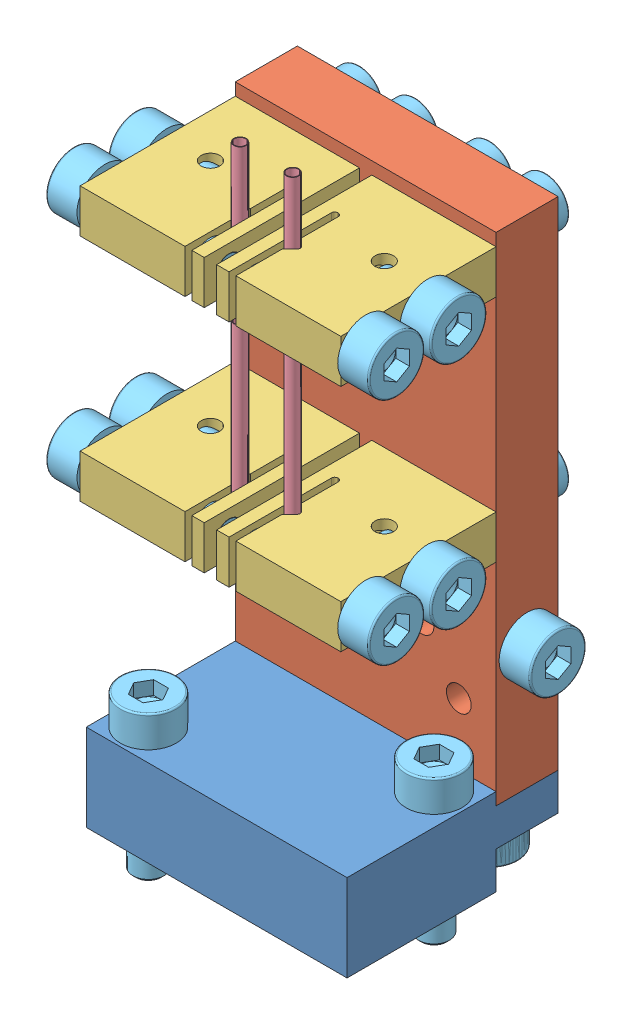
SolidWorks assembly OvenAssembly_r3, configuration Default. Lengths in mm.
Overall size (26 53 19.75).
32 component instances, 5 part files, 47 mates.
Components (placement in the parent):
- OvenBase_r3-1: OvenBase_r3 [Default] at (5.2062 4.9823 14.2147) size (21 7 17)
- OvenBack_r3-1: OvenBack_r3 [Default] at (5.2062 10.9823 8.2147) size (21 40 5)
- OvenSide_r3-1: OvenSide_r3 [Default] at (10.7062 46.4823 16.9647) x (0 0 1) z (-1 0 0) size (12.5 3.5 10)
- OvenSide_r3-2: OvenSide_r3 [Default] at (10.7062 27.9823 16.9647) x (0 0 1) z (-1 0 0) size (12.5 3.5 10)
- OvenTube-1: OvenTube [Default] at (7.3269 27.9823 18.7147) size (1 27 1)
- socket head cap screw_iso-10: socket head cap screw_iso [ISO 4762 M2.5 x 10 - 10N] at (18.2062 29.7323 21.2147) x (-1 0 0) z (0 0 -1) size (12.5 4.5 4.5)
- socket head cap screw_iso-12: socket head cap screw_iso [ISO 4762 M2.5 x 10 - 10N] at (18.2062 48.2323 21.2147) x (-1 0 0) z (0 0 -1) size (12.5 4.5 4.5)
- socket head cap screw_iso-17: socket head cap screw_iso [ISO 4762 M2.5 x 6 - 6N] at (12.7062 5.4823 8.2147) x (0 1 0) z (0 0 1) size (8.5 4.5 4.5)
- socket head cap screw_iso-18: socket head cap screw_iso [ISO 4762 M2.5 x 6 - 6N] at (-2.2938 5.4823 8.2147) x (0 1 0) z (0 0 1) size (8.5 4.5 4.5)
- socket head cap screw_iso-19: socket head cap screw_iso [ISO 4762 M2.5 x 4 - 4N] at (18.2062 48.2323 16.2147) x (-1 0 0) z (0 0 -1) size (6.5 4.5 4.5)
- socket head cap screw_iso-20: socket head cap screw_iso [ISO 4762 M2.5 x 4 - 4N] at (18.2062 29.7323 16.2147) x (-1 0 0) z (0 0 -1) size (6.5 4.5 4.5)
- socket head cap screw_iso-21: socket head cap screw_iso [ISO 4762 M2.5 x 10 - 10N] at (-2.7938 14.4823 20.2147) x (0 -1 0) z (0 0 1) size (12.5 4.5 4.5)
- socket head cap screw_iso-22: socket head cap screw_iso [ISO 4762 M2.5 x 10 - 10N] at (13.2062 14.4823 13.2147) x (0 -1 0) z (0 0 1) size (12.5 4.5 4.5)
- OvenSide_r3-4: OvenSide_r3 [Default] at (-0.2938 31.4823 16.9647) x (0 0 1) z (1 0 0) size (12.5 3.5 10)
- OvenTube-2: OvenTube [Default] at (3.0855 27.9823 18.7147) x (-1 0 0) z (0 0 -1) size (1 27 1)
- socket head cap screw_iso-23: socket head cap screw_iso [ISO 4762 M2.5 x 10 - 10N] at (-7.7938 48.2323 21.2147) size (12.5 4.5 4.5)
- socket head cap screw_iso-24: socket head cap screw_iso [ISO 4762 M2.5 x 10 - 10N] at (-7.7938 29.7323 21.2147) size (12.5 4.5 4.5)
- socket head cap screw_iso-25: socket head cap screw_iso [ISO 4762 M2.5 x 6 - 6N] at (-2.2938 5.4823 8.2147) x (0 1 0) z (0 0 -1) size (8.5 4.5 4.5)
- socket head cap screw_iso-26: socket head cap screw_iso [ISO 4762 M2.5 x 6 - 6N] at (12.7062 5.4823 8.2147) x (0 1 0) z (0 0 -1) size (8.5 4.5 4.5)
- socket head cap screw_iso-31: socket head cap screw_iso [ISO 4762 M2.5 x 4 - 4N] at (-7.7938 29.7323 16.2147) size (6.5 4.5 4.5)
- socket head cap screw_iso-32: socket head cap screw_iso [ISO 4762 M2.5 x 4 - 4N] at (-7.7938 48.2323 16.2147) size (6.5 4.5 4.5)
- socket head cap screw_iso-34: socket head cap screw_iso [ISO 4762 M2.5 x 4 - 4N] at (18.2062 20.9823 8.2147) x (-1 0 0) z (0 0 -1) size (6.5 4.5 4.5)
- socket head cap screw_iso-35: socket head cap screw_iso [ISO 4762 M2.5 x 4 - 4N] at (-7.7938 20.9823 8.2147) size (6.5 4.5 4.5)
- OvenSide_r3-5: OvenSide_r3 [Default] at (-0.2938 49.9823 16.9647) x (0 0 1) z (1 0 0) size (12.5 3.5 10)
- socket head cap screw_iso-45: socket head cap screw_iso [ISO 4762 M2 x 8 - 8N] at (-2.2938 48.2323 3.7147) x (0 0 1) z (-1 0 0) size (10 3.8 3.8)
- socket head cap screw_iso-46: socket head cap screw_iso [ISO 4762 M2 x 8 - 8N] at (2.2062 48.2323 3.7147) x (0 0 1) z (-1 0 0) size (10 3.8 3.8)
- socket head cap screw_iso-47: socket head cap screw_iso [ISO 4762 M2 x 8 - 8N] at (-2.2938 29.7323 3.7147) x (0 0 1) z (-1 0 0) size (10 3.8 3.8)
- socket head cap screw_iso-48: socket head cap screw_iso [ISO 4762 M2 x 8 - 8N] at (2.2062 29.7323 3.7147) x (0 0 1) z (-1 0 0) size (10 3.8 3.8)
- socket head cap screw_iso-49: socket head cap screw_iso [ISO 4762 M2 x 8 - 8N] at (8.2062 29.7323 3.7147) x (0 0 1) z (-1 0 0) size (10 3.8 3.8)
- socket head cap screw_iso-50: socket head cap screw_iso [ISO 4762 M2 x 8 - 8N] at (12.7062 29.7323 3.7147) x (0 0 1) z (-1 0 0) size (10 3.8 3.8)
- socket head cap screw_iso-51: socket head cap screw_iso [ISO 4762 M2 x 8 - 8N] at (8.2062 48.2323 3.7147) x (0 0 1) z (-1 0 0) size (10 3.8 3.8)
- socket head cap screw_iso-52: socket head cap screw_iso [ISO 4762 M2 x 8 - 8N] at (12.7062 48.2323 3.7147) x (0 0 1) z (-1 0 0) size (10 3.8 3.8)
Mates (geometry in assembly coordinates):
- Concentric1: concentric aligned: cylinder of OvenBase_r3-1 through (12.7062 7.9823 8.2147) axis (0 -1 0) radius 1.35; cylinder of OvenBack_r3-1 through (12.7062 10.9823 8.2147) axis (0 -1 0) radius 1.025
- Concentric2: concentric aligned: cylinder of OvenBase_r3-1 through (-2.2938 7.9823 8.2147) axis (0 -1 0) radius 1.35; cylinder of OvenBack_r3-1 through (-2.2938 10.9823 8.2147) axis (0 -1 0) radius 1.025
- Coincident1: coincident anti-aligned: plane of OvenBase_r3-1 through (5.2062 10.9823 14.2147) normal (0 1 0); plane of OvenBack_r3-1 through (5.2062 10.9823 8.2147) normal (0 -1 0)
- Concentric3: concentric aligned: cylinder of OvenBack_r3-1 through (12.7062 48.2323 5.7147) axis (0 0 -1) radius 1.1; cylinder of OvenSide_r3-1 through (12.7062 48.2323 10.7147) axis (0 0 -1) radius 0.8
- Parallel1: parallel aligned: cylinder of OvenBack_r3-1 through (-2.2938 48.2323 5.7147) axis (0 0 -1) radius 1.1; cylinder of OvenSide_r3-1 through (8.2062 48.2323 10.7147) axis (0 0 -1) radius 0.8
- Coincident2: coincident anti-aligned: plane of OvenBack_r3-1 through (-5.2938 50.9823 10.7147) normal (0 0 1); plane of OvenSide_r3-1 through (15.7062 49.9823 10.7147) normal (0 0 -1)
- Concentric5: concentric aligned: cylinder of OvenBack_r3-1 through (12.7062 29.7323 5.7147) axis (0 0 -1) radius 1.1; cylinder of OvenSide_r3-2 through (12.7062 29.7323 10.7147) axis (0 0 -1) radius 0.8
- Concentric6: concentric aligned: cylinder of OvenSide_r3-2 through (8.2062 29.7323 10.7147) axis (0 0 -1) radius 0.8; cylinder of OvenBack_r3-1 through (8.2062 29.7323 5.7147) axis (0 0 -1) radius 1.1
- Coincident3: coincident anti-aligned: plane of OvenBack_r3-1 through (-5.2938 50.9823 10.7147) normal (0 0 1); plane of OvenSide_r3-2 through (15.7062 31.4823 10.7147) normal (0 0 -1)
- Tangent1: tangent anti-aligned: plane of OvenSide_r3-1 through (8.4951 46.4823 19.1757) normal (-0.707107 0 0.707107); cylinder of OvenTube-1 through (7.3269 54.9823 18.7147) axis (0 -1 0) radius 0.5
- Coincident4: coincident aligned: plane of OvenSide_r3-2 through (10.7062 27.9823 16.9647) normal (0 -1 0); plane of OvenTube-1 through (7.3269 27.9823 18.7147) normal (0 -1 0)
- Concentric171: concentric aligned: cylinder of OvenSide_r3-2 through (15.7062 29.7323 21.2147) axis (1 0 0) radius 1.35; cylinder of socket head cap screw_iso-10 through (49.9562 29.7323 21.2147) axis (1 0 0) radius 1.25
- Coincident141: coincident anti-aligned: plane of OvenSide_r3-2 through (15.7062 31.4823 10.7147) normal (1 0 0); plane of socket head cap screw_iso-10 through (15.7062 31.9823 21.2147) normal (-1 0 0)
- Concentric241: concentric aligned: cylinder of OvenBase_r3-1 through (12.7062 7.9823 8.2147) axis (0 -1 0) radius 1.35; cylinder of socket head cap screw_iso-17 through (12.7062 -26.2677 8.2147) axis (0 -1 0) radius 1.25
- Coincident211: coincident anti-aligned: plane of OvenBase_r3-1 through (5.2062 7.9823 14.2147) normal (0 -1 0); plane of socket head cap screw_iso-17 through (10.4562 7.9823 8.2147) normal (0 1 0)
- Concentric251: concentric aligned: cylinder of OvenBase_r3-1 through (-2.2938 7.9823 8.2147) axis (0 -1 0) radius 1.35; cylinder of socket head cap screw_iso-18 through (-2.2938 -26.2677 8.2147) axis (0 -1 0) radius 1.25
- Coincident221: coincident anti-aligned: plane of OvenBase_r3-1 through (5.2062 7.9823 14.2147) normal (0 -1 0); plane of socket head cap screw_iso-18 through (-4.5438 7.9823 8.2147) normal (0 1 0)
- Concentric261: concentric aligned: cylinder of OvenSide_r3-1 through (15.7062 48.2323 16.2147) axis (1 0 0) radius 1.025; cylinder of socket head cap screw_iso-19 through (49.9562 48.2323 16.2147) axis (1 0 0) radius 2.25
- Coincident231: coincident anti-aligned: plane of OvenSide_r3-1 through (15.7062 49.9823 10.7147) normal (1 0 0); plane of socket head cap screw_iso-19 through (15.7062 50.4823 16.2147) normal (-1 0 0)
- Concentric271: concentric aligned: cylinder of OvenSide_r3-2 through (15.7062 29.7323 16.2147) axis (1 0 0) radius 1.025; cylinder of socket head cap screw_iso-20 through (49.9562 29.7323 16.2147) axis (1 0 0) radius 2.25
- Coincident241: coincident anti-aligned: plane of OvenSide_r3-2 through (15.7062 31.4823 10.7147) normal (1 0 0); plane of socket head cap screw_iso-20 through (15.7062 31.9823 16.2147) normal (-1 0 0)
- Concentric281: concentric aligned: cylinder of OvenBase_r3-1 through (-2.7938 11.9823 20.2147) axis (0 1 0) radius 1.35; cylinder of socket head cap screw_iso-21 through (-2.7938 46.2323 20.2147) axis (0 1 0) radius 1.25
- Coincident251: coincident anti-aligned: plane of OvenBase_r3-1 through (5.2062 11.9823 14.2147) normal (0 1 0); plane of socket head cap screw_iso-21 through (-0.5438 11.9823 20.2147) normal (0 -1 0)
- Concentric291: concentric aligned: cylinder of OvenBase_r3-1 through (13.2062 11.9823 13.2147) axis (0 1 0) radius 1.35; cylinder of socket head cap screw_iso-22 through (13.2062 46.2323 13.2147) axis (0 1 0) radius 1.25
- Coincident261: coincident anti-aligned: plane of OvenBase_r3-1 through (5.2062 11.9823 14.2147) normal (0 1 0); plane of socket head cap screw_iso-22 through (15.4562 11.9823 13.2147) normal (0 -1 0)
- Tangent2: tangent anti-aligned: plane of OvenSide_r3-1 through (10.2451 46.4823 16.5036) normal (-0.707107 0 -0.707107); cylinder of OvenTube-1 through (7.3269 54.9823 18.7147) axis (0 -1 0) radius 0.5
- Concentric2931: concentric aligned: cylinder of OvenBack_r3-1 through (15.7062 20.9823 8.2147) axis (1 0 0) radius 1.025; cylinder of socket head cap screw_iso-34 through (49.9562 20.9823 8.2147) axis (1 0 0) radius 2.25
- Coincident2631: coincident anti-aligned: plane of OvenBack_r3-1 through (15.7062 50.9823 5.7147) normal (1 0 0); plane of socket head cap screw_iso-34 through (15.7062 23.2323 8.2147) normal (-1 0 0)
- Parallel2: parallel anti-aligned: plane of OvenTube-1 through (7.3269 27.9823 18.7147) normal (0 0 1); plane of assembly through (0 0 -22.2853) normal (0 0 -1)
- Concentric31912: concentric aligned: cylinder of OvenSide_r3-1 through (15.7062 48.2323 21.2147) axis (1 0 0) radius 1.35; cylinder of socket head cap screw_iso-12 through (49.9562 48.2323 21.2147) axis (1 0 0) radius 1.25
- Coincident28903: coincident anti-aligned: plane of OvenSide_r3-1 through (15.7062 49.9823 10.7147) normal (1 0 0); plane of socket head cap screw_iso-12 through (15.7062 50.4823 21.2147) normal (-1 0 0)
- Concentric320171: concentric aligned: cylinder of OvenBack_r3-1 through (12.7062 48.2323 5.7147) axis (0 0 -1) radius 1.1; cylinder of socket head cap screw_iso-52 through (12.7062 48.2323 -28.0353) axis (0 0 -1) radius 1
- Coincident290081: coincident anti-aligned: plane of OvenBack_r3-1 through (-5.2938 50.9823 5.7147) normal (0 0 -1); plane of socket head cap screw_iso-52 through (12.7062 50.1323 5.7147) normal (0 0 1)
- Concentric320181: concentric aligned: cylinder of OvenBack_r3-1 through (-2.2938 48.2323 5.7147) axis (0 0 -1) radius 1.1; cylinder of socket head cap screw_iso-45 through (-2.2938 48.2323 -28.0353) axis (0 0 -1) radius 1
- Coincident290091: coincident anti-aligned: plane of OvenBack_r3-1 through (-5.2938 50.9823 5.7147) normal (0 0 -1); plane of socket head cap screw_iso-45 through (-2.2938 50.1323 5.7147) normal (0 0 1)
- Concentric320191: concentric aligned: cylinder of OvenBack_r3-1 through (12.7062 29.7323 5.7147) axis (0 0 -1) radius 1.1; cylinder of socket head cap screw_iso-50 through (12.7062 29.7323 -28.0353) axis (0 0 -1) radius 1
- Coincident290101: coincident anti-aligned: plane of OvenBack_r3-1 through (-5.2938 50.9823 5.7147) normal (0 0 -1); plane of socket head cap screw_iso-50 through (12.7062 31.6323 5.7147) normal (0 0 1)
- Concentric320201: concentric aligned: cylinder of OvenBack_r3-1 through (-2.2938 29.7323 5.7147) axis (0 0 -1) radius 1.1; cylinder of socket head cap screw_iso-47 through (-2.2938 29.7323 -28.0353) axis (0 0 -1) radius 1
- Coincident290111: coincident anti-aligned: plane of OvenBack_r3-1 through (-5.2938 50.9823 5.7147) normal (0 0 -1); plane of socket head cap screw_iso-47 through (-2.2938 31.6323 5.7147) normal (0 0 1)
- Concentric320211: concentric aligned: cylinder of OvenBack_r3-1 through (8.2062 48.2323 5.7147) axis (0 0 -1) radius 1.1; cylinder of socket head cap screw_iso-51 through (8.2062 48.2323 -28.0353) axis (0 0 -1) radius 1
- Coincident290121: coincident anti-aligned: plane of OvenBack_r3-1 through (-5.2938 50.9823 5.7147) normal (0 0 -1); plane of socket head cap screw_iso-51 through (8.2062 50.1323 5.7147) normal (0 0 1)
- Concentric320221: concentric aligned: cylinder of OvenBack_r3-1 through (2.2062 48.2323 5.7147) axis (0 0 -1) radius 1.1; cylinder of socket head cap screw_iso-46 through (2.2062 48.2323 -28.0353) axis (0 0 -1) radius 1
- Coincident290131: coincident anti-aligned: plane of OvenBack_r3-1 through (-5.2938 50.9823 5.7147) normal (0 0 -1); plane of socket head cap screw_iso-46 through (2.2062 50.1323 5.7147) normal (0 0 1)
- Concentric320231: concentric aligned: cylinder of OvenBack_r3-1 through (8.2062 29.7323 5.7147) axis (0 0 -1) radius 1.1; cylinder of socket head cap screw_iso-49 through (8.2062 29.7323 -28.0353) axis (0 0 -1) radius 1
- Coincident290141: coincident anti-aligned: plane of OvenBack_r3-1 through (-5.2938 50.9823 5.7147) normal (0 0 -1); plane of socket head cap screw_iso-49 through (8.2062 31.6323 5.7147) normal (0 0 1)
- Concentric320241: concentric aligned: cylinder of OvenBack_r3-1 through (2.2062 29.7323 5.7147) axis (0 0 -1) radius 1.1; cylinder of socket head cap screw_iso-48 through (2.2062 29.7323 -28.0353) axis (0 0 -1) radius 1
- Coincident290151: coincident anti-aligned: plane of OvenBack_r3-1 through (-5.2938 50.9823 5.7147) normal (0 0 -1); plane of socket head cap screw_iso-48 through (2.2062 31.6323 5.7147) normal (0 0 1)
